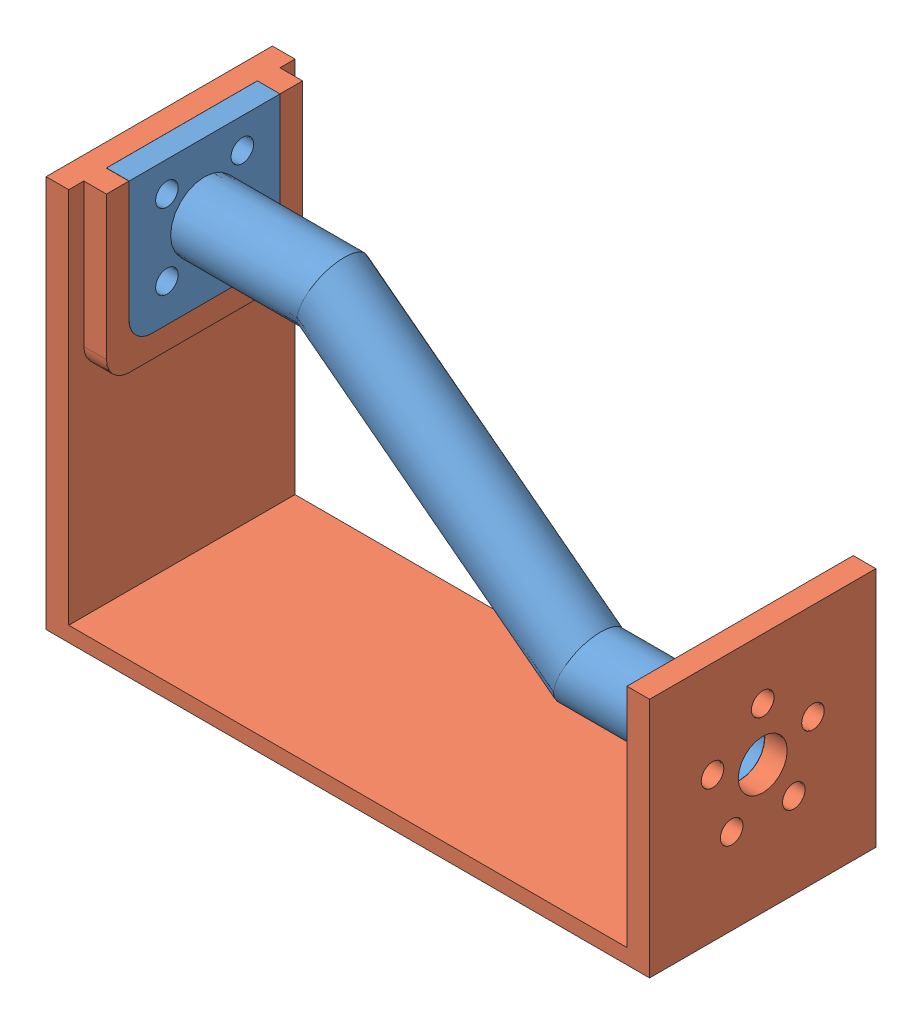
SolidWorks assembly Assem6, configuration Default. Lengths in mm.
Overall size (80 52.03 30).
2 component instances, 2 part files, 0 mates.
Components (placement in the parent):
- PART-1: PART [Default] at origin size (74.38 45 20)
- twoValves-1: twoValves [Default] at (36.9657 -42.5277 -0.0257) size (80 52 30)
